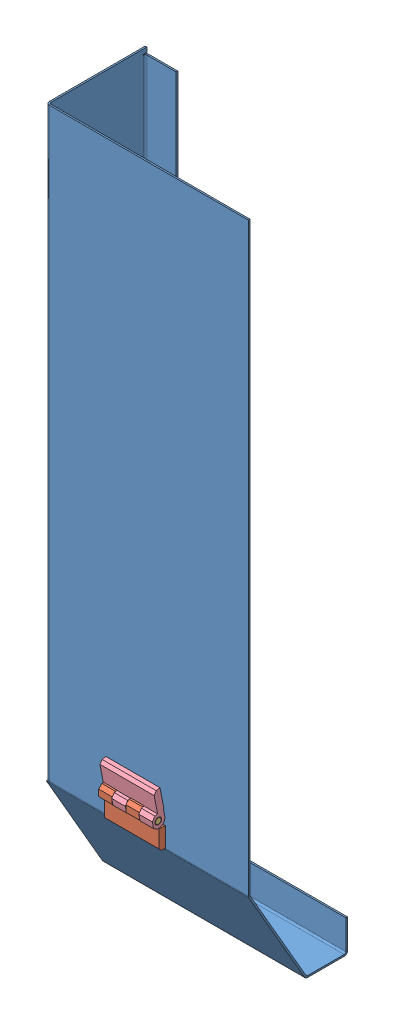
SolidWorks assembly Boite, configuration Défaut. Lengths in mm.
Overall size (186.71 632.25 110.43).
5 component instances, 4 part files, 3 mates.
Components (placement in the parent):
- Demi boite gauche-1: Demi boite gauche [Défaut] at (-126.5656 -335.8817 -45.75) size (186.71 632.25 91.5)
- Charniere EMKA 50 entraxe 30 M6 x12-1: Charniere EMKA 50 entraxe 30 M6 x12 [Défaut] at (-43.0656 -278.2583 47.9741) x (0 -1 0) z (-1 0 0) size (53.08 28.99 50)
  - Fixation gauche-1: Fixation gauche [Default] at (-57.4432 -2.2241 0) size (31 23.5 50)
  - Axe-1: Axe [Default] at (-57.4432 -2.2241 0) size (6 6 50)
  - Fixation droite-1: Fixation droite [Default] at (-58.6858 -2.1042 0) x (-0.981557 0.191168 0) z (0 0 -1) size (31 23.5 50)
Mates (geometry in assembly coordinates):
- Coïncidente1: coincident: plane of Demi boite gauche-1 through (-126.5656 294.1183 45.75) normal (0 0 1); plane of Charniere EMKA 50 entraxe 30 M6 x12-1/Fixation gauche-1 through (-30.5656 -214.8151 45.75) normal (0 0 -1)
- Distance1: distance = 60 mm: plane of Charniere EMKA 50 entraxe 30 M6 x12-1/Fixation gauche-1 through (-68.0656 -220.8151 45.75) normal (-1 0 0); plane of Demi boite gauche-1 through (-128.0656 294.1183 -45.75) normal (-1 0 0)
- Coïncidente3: coincident anti-aligned: line of Demi boite gauche-1 through (-125.0656 -245.8151 45.75) axis (1 0 0); line of Charniere EMKA 50 entraxe 30 M6 x12-1/Fixation gauche-1 through (-18.0656 -245.8151 45.75) axis (-1 0 0)
